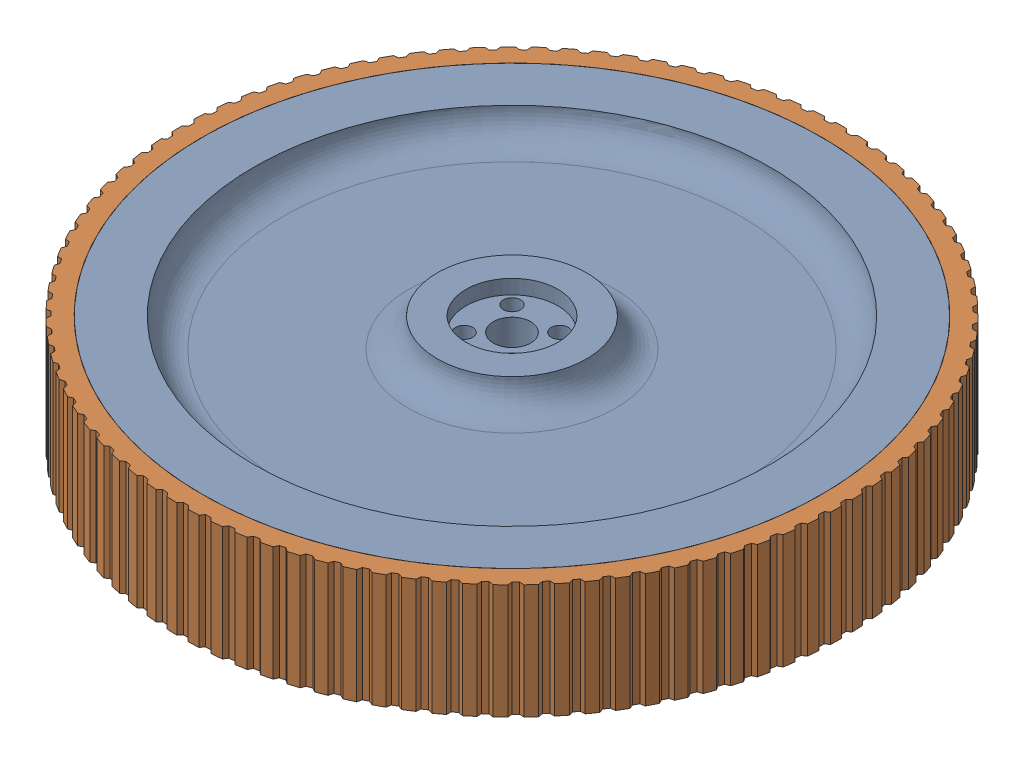
SolidWorks assembly FrontWheel_ASM_Rev2, configuration Default. Lengths in mm.
Overall size (230 40 229.98).
3 component instances, 3 part files, 4 mates.
Components (placement in the parent):
- front Rim V2-1: front Rim V2 [Default] at (47.1924 52.6298 115.3743) size (216 40 216)
- stupid tire v4-1: stupid tire v4 [Default] at (47.1924 72.6298 115.3743) x (0 1 0) z (0.164831 0 0.986322) (suppressed, hidden)
- tire_silicon-1: tire_silicon [Default] at (47.1924 72.6298 115.3743) x (0 1 0) z (0 0 1) size (40 230 229.98)
Mates (geometry in assembly coordinates):
- Concentric1: concentric anti-aligned: cylinder of front Rim stupid-1 through (47.1924 92.6298 115.3743) axis (0 -1 0) radius 105; cylinder of stupid tire v4-1 through (47.1924 94.6298 115.3743) axis (0 1 0) radius 105.05
- Width1: width anti-aligned: plane of front Rim stupid-1 through (47.1924 52.6298 115.3743) normal (0 -1 0); plane of stupid tire v4-1 through (47.1924 92.6298 115.3743) normal (0 1 0); plane of front Rim stupid-1 through (-59.429 92.6298 133.1925) normal (0 1 0); plane of stupid tire v4-1 through (-66.2346 52.6298 134.3298) normal (0 -1 0)
- Concentric2: concentric anti-aligned: cylinder of front Rim stupid-1 through (47.1924 92.6298 115.3743) axis (0 -1 0) radius 105; cylinder of tire_silicon-1 through (47.1924 94.6298 115.3743) axis (0 1 0) radius 105
- Width2: width anti-aligned: plane of front Rim stupid-1 through (47.1924 52.6298 115.3743) normal (0 -1 0); plane of front Rim stupid-1 through (47.1924 92.6298 115.3743) normal (0 1 0); plane of tire_silicon-1 through (-60.8576 92.6298 115.3743) normal (0 1 0); plane of tire_silicon-1 through (-67.8076 52.6298 115.3743) normal (0 -1 0)
